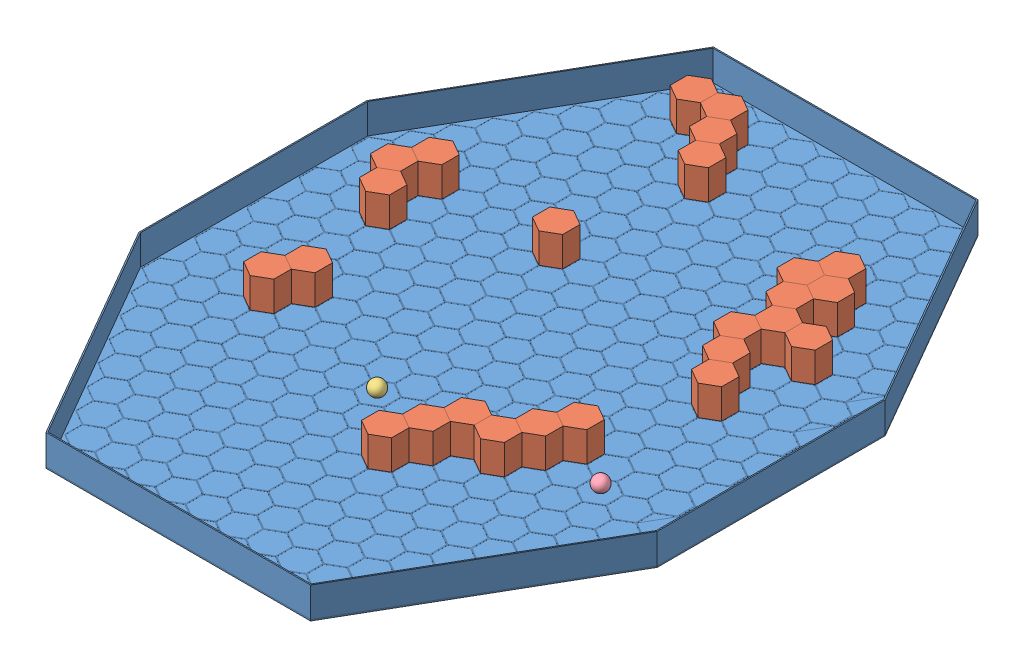
SolidWorks assembly midentropy, configuration Default. Lengths in mm.
Overall size (2643.05 174.58 3403.6).
28 component instances, 4 part files, 77 mates.
Components (placement in the parent):
- MazeFloor-1: MazeFloor [Default] at origin size (2643.05 158.75 3403.6)
- obstacle-1: obstacle [Default] at (-923.8759 0 533.4) x (0.866025 0 -0.5) z (0.5 0 0.866025) size (177.8 152.4 153.98)
- obstacle-4: obstacle [Default] at (-769.8966 0 533.4) x (0.866025 0 -0.5) z (0.5 0 0.866025) size (177.8 152.4 153.98)
- obstacle-6: obstacle [Default] at (-692.9069 0 400.05) x (0.866025 0 -0.5) z (0.5 0 0.866025) size (177.8 152.4 153.98)
- obstacle-8: obstacle [Default] at (-615.9173 0 266.7) x (0.866025 0 -0.5) z (0.5 0 0.866025) size (177.8 152.4 153.98)
- obstacle-10: obstacle [Default] at (-1000.8656 0 666.75) x (0.866025 0 -0.5) z (0.5 0 0.866025) size (177.8 152.4 153.98)
- obstacle-12: obstacle [Default] at (-2001.7312 0 266.7) x (0.866025 0 -0.5) z (0.5 0 0.866025) size (177.8 152.4 153.98)
- obstacle-14: obstacle [Default] at (-2232.7002 0 -400.05) x (0.866025 0 -0.5) z (0.5 0 0.866025) size (177.8 152.4 153.98)
- obstacle-16: obstacle [Default] at (-2155.7105 0 -533.4) x (0.866025 0 -0.5) z (0.5 0 0.866025) size (177.8 152.4 153.98)
- obstacle-18: obstacle [Default] at (-1770.7622 0 -1466.85) x (0.866025 0 -0.5) z (0.5 0 0.866025) size (177.8 152.4 153.98)
- obstacle-20: obstacle [Default] at (-1616.7829 0 -1466.85) x (0.866025 0 -0.5) z (0.5 0 0.866025) size (177.8 152.4 153.98)
- obstacle-22: obstacle [Default] at (-1539.7932 0 -1333.5) x (0.866025 0 -0.5) z (0.5 0 0.866025) size (177.8 152.4 153.98)
- obstacle-24: obstacle [Default] at (-1462.8035 0 -1200.15) x (0.866025 0 -0.5) z (0.5 0 0.866025) size (177.8 152.4 153.98)
- obstacle-26: obstacle [Default] at (-615.9173 0 -1066.8) x (0.866025 0 -0.5) z (0.5 0 0.866025) size (177.8 152.4 153.98)
- obstacle-30: obstacle [Default] at (-692.9069 0 -933.45) x (0.866025 0 -0.5) z (0.5 0 0.866025) size (177.8 152.4 153.98)
- obstacle-33: obstacle [Default] at (-538.9276 0 -933.45) x (0.866025 0 -0.5) z (0.5 0 0.866025) size (177.8 152.4 153.98)
- obstacle-35: obstacle [Default] at (-615.9173 0 -800.1) x (0.866025 0 -0.5) z (0.5 0 0.866025) size (177.8 152.4 153.98)
- obstacle-37: obstacle [Default] at (-538.9276 0 -666.75) x (0.866025 0 -0.5) z (0.5 0 0.866025) size (177.8 152.4 153.98)
- obstacle-39: obstacle [Default] at (-615.9173 0 -533.4) x (0.866025 0 -0.5) z (0.5 0 0.866025) size (177.8 152.4 153.98)
- obstacle-41: obstacle [Default] at (-538.9276 0 -400.05) x (0.866025 0 -0.5) z (0.5 0 0.866025) size (177.8 152.4 153.98)
- obstacle-43: obstacle [Default] at (-384.9483 0 -666.75) x (0.866025 0 -0.5) z (0.5 0 0.866025) size (177.8 152.4 153.98)
- obstacle-45: obstacle [Default] at (-1077.8552 0 800.1) x (0.866025 0 -0.5) z (0.5 0 0.866025) size (177.8 152.4 153.98)
- obstacle-47: obstacle [Default] at (-2155.7105 0 -266.7) x (0.866025 0 -0.5) z (0.5 0 0.866025) size (177.8 152.4 153.98)
- obstacle-49: obstacle [Default] at (-2078.7208 0 400.05) x (0.866025 0 -0.5) z (0.5 0 0.866025) size (177.8 152.4 153.98)
- obstacle-51: obstacle [Default] at (-461.938 0 -266.7) x (0.866025 0 -0.5) z (0.5 0 0.866025) size (177.8 152.4 153.98)
- obstacle-53: obstacle [Default] at (-1539.7932 0 -533.4) x (0.866025 0 -0.5) z (0.5 0 0.866025) size (177.8 152.4 153.98)
- predator-1: predator [Default] at (-1374.0362 38.1 545.7665) x (0.296813 0.095297 -0.950169) z (0.19175 0.968794 0.157064) size (76.2 76.2 76.2)
- prey-1: prey [Default] at (-381.9944 38.1 397.9635) x (0.544146 0.827256 0.139833) z (0.139833 -0.253761 0.957106) size (76.2 76.2 76.2)
Mates (geometry in assembly coordinates):
- Coincident1: coincident anti-aligned: plane of MazeFloor-1 through (-923.8759 0 533.4) normal (0 1 0); plane of obstacle-1 through (-923.8759 0 533.4) normal (0 -1 0)
- Coincident2: coincident: line of MazeFloor-1 through (-846.8863 0 577.85) axis (-0.866025 0 0.5); plane of obstacle-1 through (-923.8759 152.4 622.3) normal (0.5 0 0.866025)
- Coincident3: coincident: line of MazeFloor-1 through (-846.8863 0 488.95) axis (0 0 1); plane of obstacle-1 through (-846.8863 152.4 577.85) normal (1 0 0)
- Coincident8: coincident anti-aligned: plane of MazeFloor-1 through (-769.8966 0 533.4) normal (0 1 0); plane of obstacle-4 through (-769.8966 0 533.4) normal (0 -1 0)
- Coincident9: coincident: line of MazeFloor-1 through (-692.9069 0 577.85) axis (-0.866025 0 0.5); plane of obstacle-4 through (-769.8966 152.4 622.3) normal (0.5 0 0.866025)
- Coincident10: coincident: line of MazeFloor-1 through (-692.9069 0 577.85) axis (0 0 -1); plane of obstacle-4 through (-692.9069 152.4 577.85) normal (1 0 0)
- Coincident11: coincident anti-aligned: plane of MazeFloor-1 through (-692.9069 0 400.05) normal (0 1 0); plane of obstacle-6 through (-692.9069 0 400.05) normal (0 -1 0)
- Coincident12: coincident: line of MazeFloor-1 through (-692.9069 0 488.95) axis (0.866025 0 -0.5); plane of obstacle-6 through (-692.9069 152.4 488.95) normal (0.5 0 0.866025)
- Coincident13: coincident: line of MazeFloor-1 through (-615.9173 0 355.6) axis (0 0 1); plane of obstacle-6 through (-615.9173 152.4 444.5) normal (1 0 0)
- Coincident14: coincident anti-aligned: plane of MazeFloor-1 through (-615.9173 0 266.7) normal (0 1 0); plane of obstacle-8 through (-615.9173 0 266.7) normal (0 -1 0)
- Coincident15: coincident: line of MazeFloor-1 through (-538.9276 0 311.15) axis (-0.866025 0 0.5); plane of obstacle-8 through (-615.9173 152.4 355.6) normal (0.5 0 0.866025)
- Coincident16: coincident: line of MazeFloor-1 through (-538.9276 0 222.25) axis (0 0 1); plane of obstacle-8 through (-538.9276 152.4 311.15) normal (1 0 0)
- Coincident17: coincident anti-aligned: plane of MazeFloor-1 through (-1000.8656 0 666.75) normal (0 1 0); plane of obstacle-10 through (-1000.8656 0 666.75) normal (0 -1 0)
- Coincident19: coincident: line of MazeFloor-1 through (-1000.8656 0 755.65) axis (0.866025 0 -0.5); plane of obstacle-10 through (-1000.8656 152.4 755.65) normal (0.5 0 0.866025)
- Coincident20: coincident: line of MazeFloor-1 through (-923.8759 0 711.2) axis (0 0 -1); plane of obstacle-10 through (-923.8759 152.4 711.2) normal (1 0 0)
- Coincident21: coincident anti-aligned: plane of MazeFloor-1 through (-2001.7312 0 266.7) normal (0 1 0); plane of obstacle-12 through (-2001.7312 0 266.7) normal (0 -1 0)
- Coincident22: coincident: line of MazeFloor-1 through (-1924.7415 0 311.15) axis (-0.866025 0 0.5); plane of obstacle-12 through (-2001.7312 152.4 355.6) normal (0.5 0 0.866025)
- Coincident23: coincident: line of MazeFloor-1 through (-1924.7415 0 311.15) axis (0 0 -1); plane of obstacle-12 through (-1924.7415 152.4 311.15) normal (1 0 0)
- Coincident24: coincident anti-aligned: plane of MazeFloor-1 through (-2232.7002 0 -400.05) normal (0 1 0); plane of obstacle-14 through (-2232.7002 0 -400.05) normal (0 -1 0)
- Coincident25: coincident: line of MazeFloor-1 through (-2155.7105 0 -355.6) axis (-0.866025 0 0.5); plane of obstacle-14 through (-2232.7002 152.4 -311.15) normal (0.5 0 0.866025)
- Coincident26: coincident: line of MazeFloor-1 through (-2155.7105 0 -355.6) axis (0 0 -1); plane of obstacle-14 through (-2155.7105 152.4 -355.6) normal (1 0 0)
- Coincident27: coincident anti-aligned: plane of MazeFloor-1 through (-2155.7105 0 -533.4) normal (0 1 0); plane of obstacle-16 through (-2155.7105 0 -533.4) normal (0 -1 0)
- Coincident28: coincident: line of MazeFloor-1 through (-2155.7105 0 -444.5) axis (0.866025 0 -0.5); plane of obstacle-16 through (-2155.7105 152.4 -444.5) normal (0.5 0 0.866025)
- Coincident29: coincident: line of MazeFloor-1 through (-2078.7208 0 -488.95) axis (0 0 -1); plane of obstacle-16 through (-2078.7208 152.4 -488.95) normal (1 0 0)
- Coincident30: coincident anti-aligned: plane of MazeFloor-1 through (-1770.7622 0 -1466.85) normal (0 1 0); plane of obstacle-18 through (-1770.7622 0 -1466.85) normal (0 -1 0)
- Coincident31: coincident: line of MazeFloor-1 through (-1693.7725 0 -1422.4) axis (-0.866025 0 0.5); plane of obstacle-18 through (-1770.7622 152.4 -1377.95) normal (0.5 0 0.866025)
- Coincident32: coincident: line of MazeFloor-1 through (-1693.7725 0 -1422.4) axis (0 0 -1); plane of obstacle-18 through (-1693.7725 152.4 -1422.4) normal (1 0 0)
- Coincident33: coincident anti-aligned: plane of MazeFloor-1 through (-1616.7829 0 -1466.85) normal (0 1 0); plane of obstacle-20 through (-1616.7829 0 -1466.85) normal (0 -1 0)
- Coincident35: coincident: line of MazeFloor-1 through (-1539.7932 0 -1422.4) axis (-0.866025 0 0.5); plane of obstacle-20 through (-1616.7829 152.4 -1377.95) normal (0.5 0 0.866025)
- Coincident36: coincident: line of MazeFloor-1 through (-1539.7932 0 -1511.3) axis (0 0 1); plane of obstacle-20 through (-1539.7932 152.4 -1422.4) normal (1 0 0)
- Coincident37: coincident anti-aligned: plane of MazeFloor-1 through (-1539.7932 0 -1333.5) normal (0 1 0); plane of obstacle-22 through (-1539.7932 0 -1333.5) normal (0 -1 0)
- Coincident38: coincident: line of MazeFloor-1 through (-1539.7932 0 -1244.6) axis (0.866025 0 -0.5); plane of obstacle-22 through (-1539.7932 152.4 -1244.6) normal (0.5 0 0.866025)
- Coincident39: coincident: line of MazeFloor-1 through (-1462.8036 0 -1289.05) axis (0 0 -1); plane of obstacle-22 through (-1462.8036 152.4 -1289.05) normal (1 0 0)
- Coincident40: coincident anti-aligned: plane of MazeFloor-1 through (-1462.8035 0 -1200.15) normal (0 1 0); plane of obstacle-24 through (-1462.8035 0 -1200.15) normal (0 -1 0)
- Coincident41: coincident: line of MazeFloor-1 through (-1385.8139 0 -1155.7) axis (-0.866025 0 0.5); plane of obstacle-24 through (-1462.8035 152.4 -1111.25) normal (0.5 0 0.866025)
- Coincident42: coincident: line of MazeFloor-1 through (-1385.8139 0 -1155.7) axis (0 0 -1); plane of obstacle-24 through (-1385.8139 152.4 -1155.7) normal (1 0 0)
- Coincident43: coincident anti-aligned: plane of MazeFloor-1 through (-615.9173 0 -1066.8) normal (0 1 0); plane of obstacle-26 through (-615.9173 0 -1066.8) normal (0 -1 0)
- Coincident44: coincident: line of MazeFloor-1 through (-615.9173 0 -977.9) axis (0.866025 0 -0.5); plane of obstacle-26 through (-615.9173 152.4 -977.9) normal (0.5 0 0.866025)
- Coincident45: coincident: line of MazeFloor-1 through (-538.9276 0 -1022.35) axis (0 0 -1); plane of obstacle-26 through (-538.9276 152.4 -1022.35) normal (1 0 0)
- Coincident49: coincident anti-aligned: plane of MazeFloor-1 through (-692.9069 0 -933.45) normal (0 1 0); plane of obstacle-30 through (-692.9069 0 -933.45) normal (0 -1 0)
- Coincident51: coincident: line of MazeFloor-1 through (-615.9173 0 -889) axis (-0.866025 0 0.5); plane of obstacle-30 through (-692.9069 152.4 -844.55) normal (0.5 0 0.866025)
- Coincident52: coincident: line of MazeFloor-1 through (-615.9173 0 -977.9) axis (0 0 1); plane of obstacle-30 through (-615.9173 152.4 -889) normal (1 0 0)
- Coincident59: coincident anti-aligned: plane of MazeFloor-1 through (-538.9276 0 -933.45) normal (0 1 0); plane of obstacle-33 through (-538.9276 0 -933.45) normal (0 -1 0)
- Coincident60: coincident: line of MazeFloor-1 through (-461.938 0 -889) axis (-0.866025 0 0.5); plane of obstacle-33 through (-538.9276 152.4 -844.55) normal (0.5 0 0.866025)
- Coincident61: coincident: line of MazeFloor-1 through (-461.938 0 -889) axis (0 0 -1); plane of obstacle-33 through (-461.938 152.4 -889) normal (1 0 0)
- Coincident62: coincident anti-aligned: plane of MazeFloor-1 through (-615.9173 0 -800.1) normal (0 1 0); plane of obstacle-35 through (-615.9173 0 -800.1) normal (0 -1 0)
- Coincident63: coincident: line of MazeFloor-1 through (-615.9173 0 -711.2) axis (0.866025 0 -0.5); plane of obstacle-35 through (-615.9173 152.4 -711.2) normal (0.5 0 0.866025)
- Coincident64: coincident: line of MazeFloor-1 through (-538.9276 0 -755.65) axis (0 0 -1); plane of obstacle-35 through (-538.9276 152.4 -755.65) normal (1 0 0)
- Coincident65: coincident anti-aligned: plane of MazeFloor-1 through (-538.9276 0 -666.75) normal (0 1 0); plane of obstacle-37 through (-538.9276 0 -666.75) normal (0 -1 0)
- Coincident67: coincident: line of MazeFloor-1 through (-461.938 0 -622.3) axis (-0.866025 0 0.5); plane of obstacle-37 through (-538.9276 152.4 -577.85) normal (0.5 0 0.866025)
- Coincident68: coincident: line of MazeFloor-1 through (-461.938 0 -622.3) axis (0 0 -1); plane of obstacle-37 through (-461.938 152.4 -622.3) normal (1 0 0)
- Coincident69: coincident anti-aligned: plane of MazeFloor-1 through (-615.9173 0 -533.4) normal (0 1 0); plane of obstacle-39 through (-615.9173 0 -533.4) normal (0 -1 0)
- Coincident70: coincident: line of MazeFloor-1 through (-615.9173 0 -444.5) axis (0.866025 0 -0.5); plane of obstacle-39 through (-615.9173 152.4 -444.5) normal (0.5 0 0.866025)
- Coincident71: coincident: line of MazeFloor-1 through (-538.9276 0 -488.95) axis (0 0 -1); plane of obstacle-39 through (-538.9276 152.4 -488.95) normal (1 0 0)
- Coincident72: coincident anti-aligned: plane of MazeFloor-1 through (-538.9276 0 -400.05) normal (0 1 0); plane of obstacle-41 through (-538.9276 0 -400.05) normal (0 -1 0)
- Coincident73: coincident: line of MazeFloor-1 through (-461.938 0 -355.6) axis (-0.866025 0 0.5); plane of obstacle-41 through (-538.9276 152.4 -311.15) normal (0.5 0 0.866025)
- Coincident74: coincident: line of MazeFloor-1 through (-461.938 0 -355.6) axis (0 0 -1); plane of obstacle-41 through (-461.938 152.4 -355.6) normal (1 0 0)
- Coincident75: coincident anti-aligned: plane of MazeFloor-1 through (-384.9483 0 -666.75) normal (0 1 0); plane of obstacle-43 through (-384.9483 0 -666.75) normal (0 -1 0)
- Coincident76: coincident: line of MazeFloor-1 through (-307.9586 0 -622.3) axis (-0.866025 0 0.5); plane of obstacle-43 through (-384.9483 152.4 -577.85) normal (0.5 0 0.866025)
- Coincident77: coincident: line of MazeFloor-1 through (-307.9586 0 -711.2) axis (0 0 1); plane of obstacle-43 through (-307.9586 152.4 -622.3) normal (1 0 0)
- Coincident78: coincident anti-aligned: plane of MazeFloor-1 through (-1077.8552 0 800.1) normal (0 1 0); plane of obstacle-45 through (-1077.8552 0 800.1) normal (0 -1 0)
- Coincident79: coincident: line of MazeFloor-1 through (-1000.8656 0 844.55) axis (-0.866025 0 0.5); plane of obstacle-45 through (-1077.8552 152.4 889) normal (0.5 0 0.866025)
- Coincident80: coincident: line of MazeFloor-1 through (-1000.8656 0 844.55) axis (0 0 -1); plane of obstacle-45 through (-1000.8656 152.4 844.55) normal (1 0 0)
- Coincident81: coincident anti-aligned: plane of MazeFloor-1 through (-2155.7105 0 -266.7) normal (0 1 0); plane of obstacle-47 through (-2155.7105 0 -266.7) normal (0 -1 0)
- Coincident82: coincident: line of MazeFloor-1 through (-2155.7105 0 -177.8) axis (0.866025 0 -0.5); plane of obstacle-47 through (-2155.7105 152.4 -177.8) normal (0.5 0 0.866025)
- Coincident83: coincident: line of MazeFloor-1 through (-2078.7208 0 -311.15) axis (0 0 1); plane of obstacle-47 through (-2078.7208 152.4 -222.25) normal (1 0 0)
- Coincident84: coincident anti-aligned: plane of MazeFloor-1 through (-2078.7208 0 400.05) normal (0 1 0); plane of obstacle-49 through (-2078.7208 0 400.05) normal (0 -1 0)
- Coincident85: coincident: line of MazeFloor-1 through (-2078.7208 0 488.95) axis (0.866025 0 -0.5); plane of obstacle-49 through (-2078.7208 152.4 488.95) normal (0.5 0 0.866025)
- Coincident86: coincident: line of MazeFloor-1 through (-2001.7312 0 355.6) axis (0 0 1); plane of obstacle-49 through (-2001.7312 152.4 444.5) normal (1 0 0)
- Coincident87: coincident anti-aligned: plane of MazeFloor-1 through (-461.938 0 -266.7) normal (0 1 0); plane of obstacle-51 through (-461.938 0 -266.7) normal (0 -1 0)
- Coincident88: coincident: line of MazeFloor-1 through (-461.938 0 -177.8) axis (0.866025 0 -0.5); plane of obstacle-51 through (-461.938 152.4 -177.8) normal (0.5 0 0.866025)
- Coincident89: coincident: line of MazeFloor-1 through (-384.9483 0 -222.25) axis (0 0 -1); plane of obstacle-51 through (-384.9483 152.4 -222.25) normal (1 0 0)
- Coincident90: coincident anti-aligned: plane of MazeFloor-1 through (-1539.7932 0 -533.4) normal (0 1 0); plane of obstacle-53 through (-1539.7932 0 -533.4) normal (0 -1 0)
- Coincident91: coincident: line of MazeFloor-1 through (-1539.7932 0 -444.5) axis (0.866025 0 -0.5); plane of obstacle-53 through (-1539.7932 152.4 -444.5) normal (0.5 0 0.866025)
- Coincident92: coincident: line of MazeFloor-1 through (-1462.8036 0 -488.95) axis (0 0 -1); plane of obstacle-53 through (-1462.8036 152.4 -488.95) normal (1 0 0)
- Tangent1: tangent anti-aligned: plane of MazeFloor-1 through (-1385.8139 0 800.1) normal (0 1 0); sphere of predator-1
- Tangent2: tangent anti-aligned: plane of MazeFloor-1 through (-307.9586 0 266.7) normal (0 1 0); sphere of prey-1
